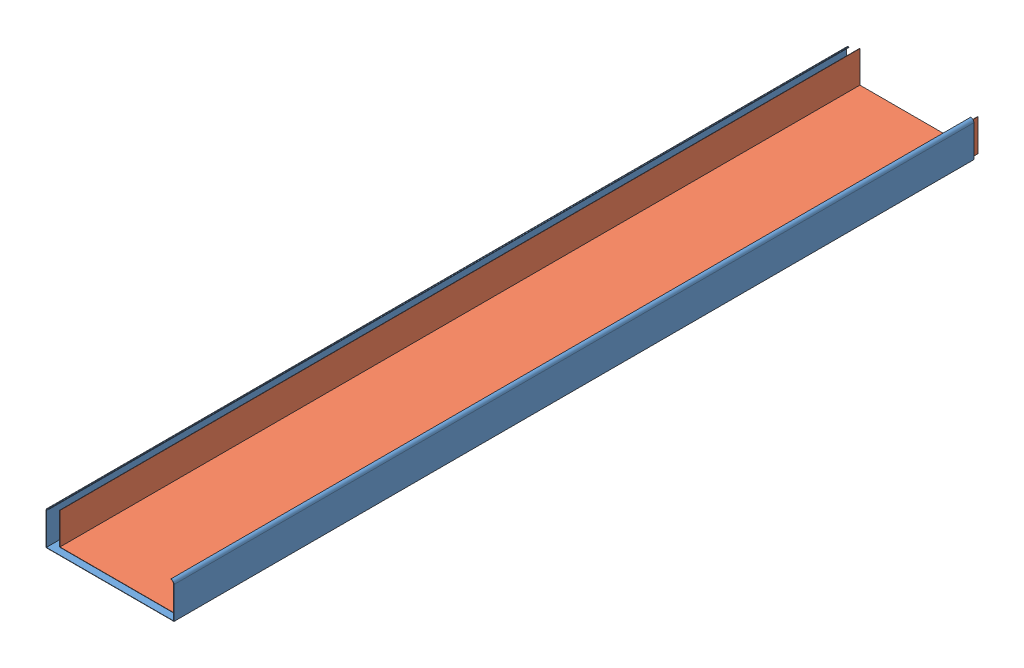
SolidWorks assembly Assem2, configuration Default. Lengths in mm.
Overall size (40 11 252.15).
2 component instances, 2 part files, 1 mates.
Components (placement in the parent):
- channel part 1-1: channel part 1 [Default] at (-12.5816 -20.1102 -108.4349) size (40 11 250)
- channel part 2-1: channel part 2 [Default] at (-11.9635 -20.0102 -110.5836) size (37 10 250)
Mates (geometry in assembly coordinates):
- Coincident1: coincident anti-aligned: plane of channel part 1-1 through (7.3184 -20.0102 141.5651) normal (0 1 0); plane of channel part 2-1 through (6.5365 -20.0102 139.4164) normal (0 -1 0)
